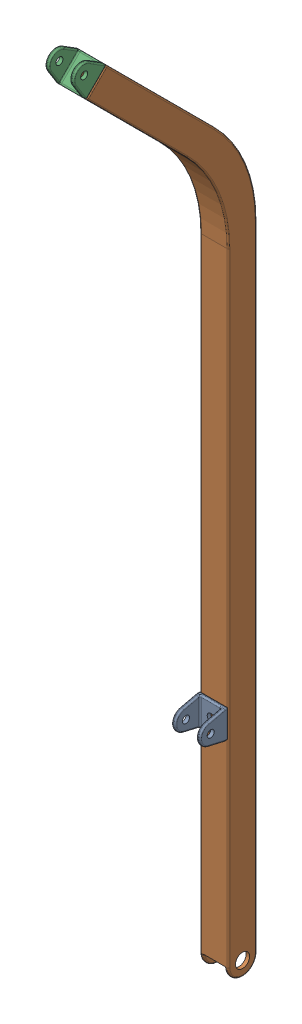
SolidWorks assembly 悬挂梁部件, configuration 默认. Lengths in mm.
Overall size (40 1240.42 268.7).
3 component instances, 2 part files, 8 mates.
Components (placement in the parent):
- U型接头-1: U型接头 [默认] at (0 -20 20) size (40 40 40)
- 悬挂梁-1: 悬挂梁 [默认] at (-20 -340 -20) x (0 -1 0) z (1 0 0) size (1211.3 239.59 40)
- U型接头-2: U型接头 [默认] at (0 857.9899 206.2742) x (1 0 0) z (0 0.707107 0.707107) size (40 40 40)
Mates (geometry in assembly coordinates):
- 重合1: coincident aligned: plane of 悬挂梁-1 through (-20 596.0285 180) normal (-1 0 0); plane of U型接头-2 through (-20 894.5388 195.6676) normal (-1 0 0)
- 重合2: coincident anti-aligned: plane of 悬挂梁-1 through (20 891.0033 192.132) normal (0 0.707107 0.707107); plane of U型接头-2 through (0 876.8612 206.2742) normal (0 -0.707107 -0.707107)
- 重合3: coincident aligned: plane of 悬挂梁-1 through (20 737.4499 38.5786) normal (0 0.707107 -0.707107); plane of U型接头-2 through (-20 894.5388 195.6676) normal (0 0.707107 -0.707107)
- 重合4: coincident aligned: plane of U型接头-1 through (-20 18.8713 25) normal (-1 0 0); plane of 悬挂梁-1 through (-20 596.0285 180) normal (-1 0 0)
- 重合5: coincident aligned: circle of U型接头-1; circle of 悬挂梁-1
- 对称2: symmetric aligned: plane of 悬挂梁-1 through (20 596.0285 180) normal (1 0 0); plane of 悬挂梁-1 through (-20 596.0285 180) normal (-1 0 0)
- 对称3: symmetric aligned: plane of 悬挂梁-1 through (20 -321.1287 -20) normal (0 0 -1); plane of 悬挂梁-1 through (20 579.46 20) normal (0 0 1)
- 重合6: coincident aligned: plane of U型接头-1 through (-20 18.8713 25) normal (0 1 0)
